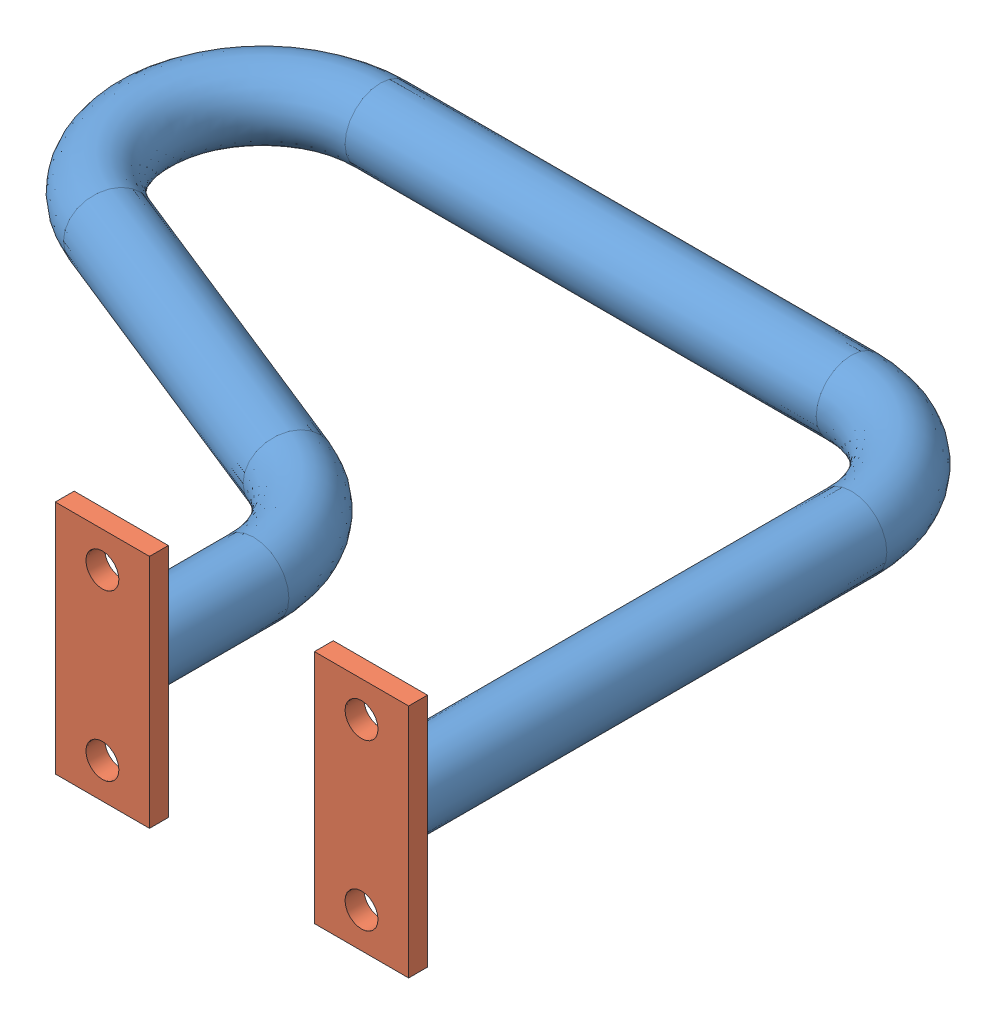
SolidWorks assembly T210-1-00(1), configuration Domyślna. Lengths in mm.
Overall size (335 100 273).
3 component instances, 2 part files, 7 mates.
Components (placement in the parent):
- pałąk ustalający 1-1: pałąk ustalający 1 [Domyślna] at origin size (330 30 265)
- płytka pałąka-1: płytka pałąka [Domyślna] at (-35 50 0) x (-1 0 0) z (0 1 0) size (40 8 100)
- płytka pałąka-2: płytka pałąka [Domyślna] at (75 50 0) x (-1 0 0) z (0 1 0) size (40 8 100)
Mates (geometry in assembly coordinates):
- Wspólnie1: coordinate: point of pałąk ustalający 1-1; point of assembly
- Wspólnie2: coincident anti-aligned: plane of pałąk ustalający 1-1 through (-55 0 0) normal (0 0 1); plane of płytka pałąka-1 through (-35 50 0) normal (0 0 -1)
- Wspólnie3: coincident aligned: cylinder of pałąk ustalający 1-1 through (-55 0 -56.1777) axis (0 0 1) radius 15; circle of płytka pałąka-1
- Równolegle1: parallel aligned: plane of płytka pałąka-1 through (-35 50 8) normal (1 0 0); plane of assembly
- Wspólnie4: coincident anti-aligned: plane of pałąk ustalający 1-1 through (55 0 0) normal (0 0 1); plane of płytka pałąka-2 through (75 50 0) normal (0 0 -1)
- Wspólnie5: coincident aligned: cylinder of pałąk ustalający 1-1 through (55 0 -200) axis (0 0 1) radius 15; circle of płytka pałąka-2
- Równolegle2: parallel anti-aligned: plane of płytka pałąka-2 through (35 50 8) normal (-1 0 0); plane of assembly
